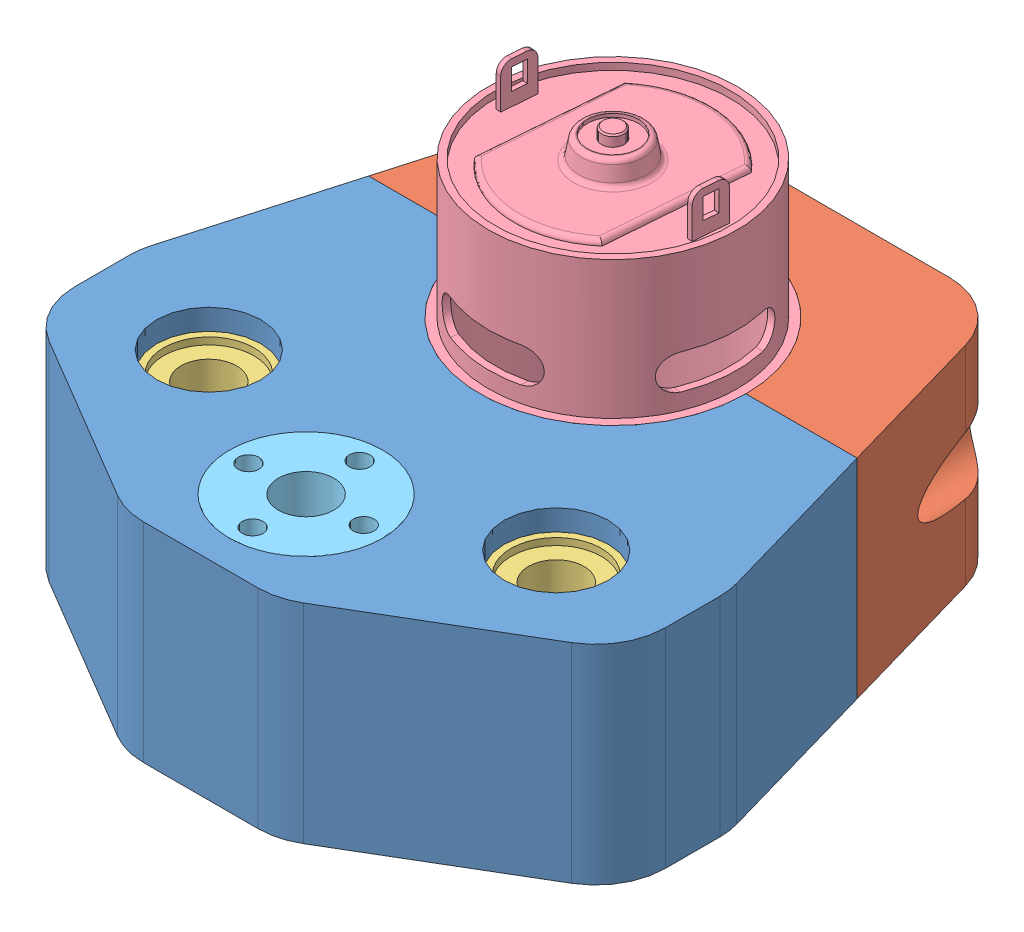
SolidWorks assembly SPINDLE_HOLDER_2, configuration Default. Lengths in mm.
Overall size (85 76.5 88.45).
6 component instances, 5 part files, 11 mates.
Components (placement in the parent):
- PartA-1: PartA [Default] at origin size (85 30 59.3)
- PartB-1: PartB [Default] x (1 0 0) z (0 1 0) size (70.3 29.15 30)
- linear_bearing-1: linear_bearing [Default] at (-25 15 33.15) x (1 0 0) z (0 -1 0) size (15 15 24)
- linear_bearing-2: linear_bearing [Default] at (25 15 33.15) x (1 0 0) z (0 -1 0) size (15 15 24)
- spindle-1: spindle [Default] at (0 -8.2 0) x (0.078415 0 -0.996921) z (0.996921 0 0.078415) size (38.3 76.5 38.3)
- trapezoidal_nut-1: trapezoidal_nut [Default] at (0 30 44.15) x (0.999297 0 -0.037497) z (0 -1 0) size (22 22 15)
Mates (geometry in assembly coordinates):
- Coincident4: coincident anti-aligned: plane of PartA-1 through (0 30 0) normal (0 0 -1); plane of Part5^SPINDLE_HOLDER_2-1 through (0 30 0) normal (0 0 1)
- Coincident5: coincident aligned: plane of PartA-1 through (0 30 0) normal (0 1 0); plane of Part5^SPINDLE_HOLDER_2-1 through (0 30 0) normal (0 1 0)
- Coincident6: coincident aligned: plane of linear_bearing-1 through (-25 26 33.15) normal (0 1 0); plane of linear_bearing-2 through (25 26 33.15) normal (0 1 0)
- Concentric1: concentric anti-aligned: cylinder of PartA-1 through (-25 30 33.15) axis (0 -1 0) radius 7.5; cylinder of linear_bearing-1 through (-25 3 33.15) axis (0 1 0) radius 7.5
- Concentric2: concentric anti-aligned: cylinder of PartA-1 through (25 30 33.15) axis (0 -1 0) radius 7.5; cylinder of linear_bearing-2 through (25 3 33.15) axis (0 1 0) radius 7.5
- Width1: width anti-aligned: plane of linear_bearing-1 through (-25 26 33.15) normal (0 1 0); plane of PartA-1 through (-25 4 33.15) normal (0 -1 0); plane of linear_bearing-1 through (0 0 0) normal (0 -1 0); plane of PartA-1 through (0 30 0) normal (0 1 0)
- Concentric3: concentric aligned: cylinder of PartA-1 through (0 30 0) axis (0 -1 0) radius 19.15; cylinder of spindle-1 through (0 -8.2 0) axis (0 -1 0) radius 19.15
- Concentric4: concentric aligned: cylinder of Part5^SPINDLE_HOLDER_2-1 through (0 30 0) axis (0 -1 0) radius 19.15; cylinder of spindle-1 through (0 -8.2 0) axis (0 -1 0) radius 19.15
- Coincident7: coincident aligned: plane of Part5^SPINDLE_HOLDER_2-1 through (0 30 0) normal (0 1 0); plane of spindle-1 through (4.481 30 -17.33) normal (0 1 0)
- Concentric5: concentric anti-aligned: cylinder of PartA-1 through (0 30 44.15) axis (0 -1 0) radius 5.15; cylinder of trapezoidal_nut-1 through (0 15 44.15) axis (0 1 0) radius 5.15
- Coincident8: coincident anti-aligned: plane of PartA-1 through (0 26 44.15) normal (0 1 0); plane of trapezoidal_nut-1 through (0 26 44.15) normal (0 -1 0)
